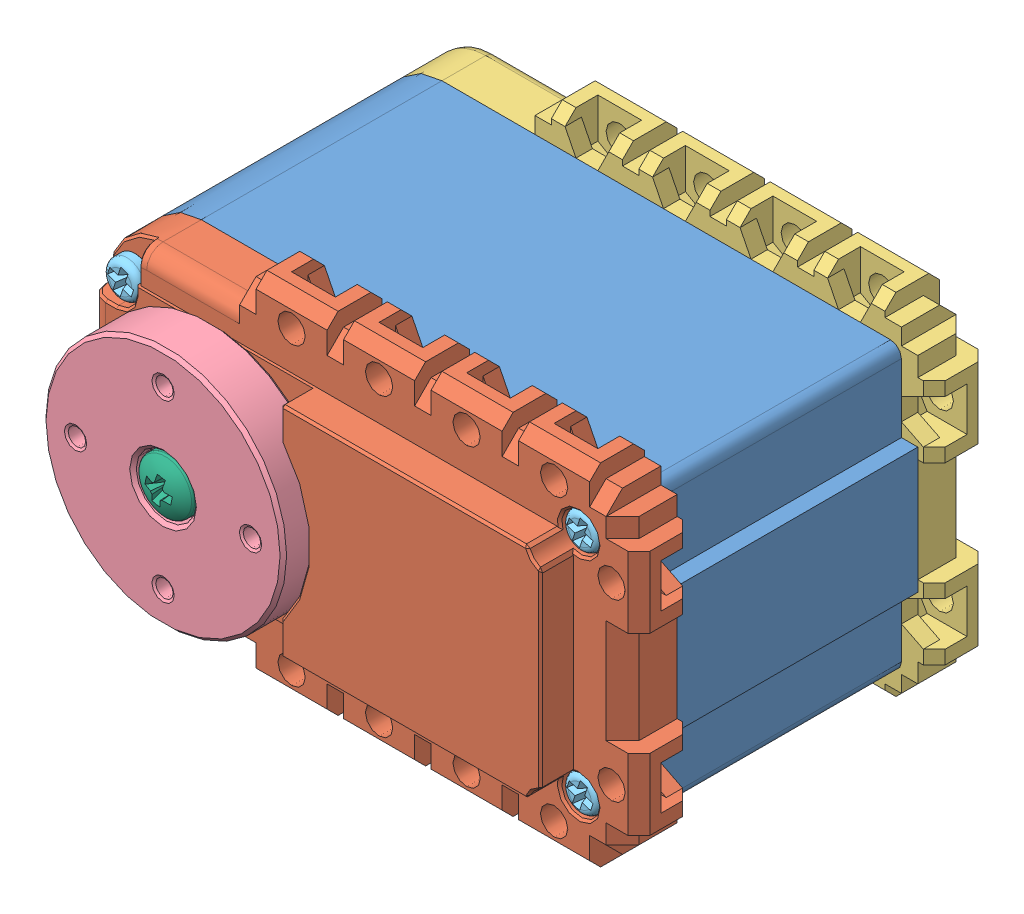
SolidWorks assembly AX-12Amotor, configuration Default. Lengths in mm.
Overall size (50 32 40.55).
9 component instances, 6 part files, 36 mates.
Components (placement in the parent):
- AX-12A-01-1: AX-12A-01 [Default] at origin size (48.5 26 22)
- AX-12A-02-1: AX-12A-02 [Default] at (0 0 13.5) size (50 32 8)
- AX-12A-03-1: AX-12A-03 [Default] at (0 0 -13.5) x (1 0 0) z (0 0 -1) size (50 32 8)
- AX-12A-04-1: AX-12A-04 [Default] at (0 0 21) size (22 22 6.7)
- SetScrew-5: SetScrew [Default] at (33 10.4 14.5) x (0.31498 0.949098 0) z (0 0 -1) size (3.3 3.3 29.44)
- SetScrew-6: SetScrew [Default] at (-9 9.25 14.5) x (0.31498 0.949098 0) z (0 0 -1) size (3.3 3.3 29.44)
- SetScrew-7: SetScrew [Default] at (-9 -9.25 14.5) x (-0.839745 -0.542981 0) z (0 0 -1) size (3.3 3.3 29.44)
- SetScrew-8: SetScrew [Default] at (33 -10.4 14.5) x (0.31498 0.949098 0) z (0 0 -1) size (3.3 3.3 29.44)
- pan head cross recess screw_iso-1: pan head cross recess screw_iso [ISO 7045 - M2.5 x 8 - Z --- 8C] at (0 0 21.6) x (0 0 -1) z (0.97903 -0.203716 0) size (10.05 5 5)
Mates (geometry in assembly coordinates):
- Coincident1: coincident: plane of AX-12A-01-1 through (0 0 11) normal (0 0 1); plane of AX-12A-02-1 through (0 0 11) normal (0 0 -1)
- Coincident2: coincident: plane of AX-12A-01-1 through (0 0 0) normal (1 0 0); plane of AX-12A-02-1 through (0 0 13.5) normal (1 0 0)
- Coincident3: coincident: plane of AX-12A-01-1 through (0 0 0) normal (0 1 0); plane of AX-12A-02-1 through (0 0 13.5) normal (0 1 0)
- Coincident4: coincident: plane of AX-12A-01-1 through (0 0 -11) normal (0 0 -1); plane of AX-12A-03-1 through (0 0 -11) normal (0 0 1)
- Coincident5: coincident: plane of AX-12A-01-1 through (0 0 0) normal (1 0 0); plane of AX-12A-03-1 through (0 0 -13.5) normal (1 0 0)
- Coincident6: coincident: plane of AX-12A-01-1 through (0 0 0) normal (0 1 0); plane of AX-12A-03-1 through (0 0 -13.5) normal (0 -1 0)
- Concentric1: concentric: cylinder of AX-12A-02-1 through (0 0 13.75) axis (0 0 1) radius 4.75; cylinder of AX-12A-04-1 through (0 0 21) axis (0 0 -1) radius 4.5
- Distance1: distance = 5 mm: plane of AX-12A-02-1 through (0 0 16) normal (0 0 1); plane of AX-12A-04-1 through (0 2.75 21) normal (0 0 1)
- Coincident7: coincident: plane of AX-12A-04-1 through (0 0 21) normal (1 0 0); plane of assembly through (0 0 0) normal (1 0 0)
- Concentric2: concentric: cylinder of AX-12A-02-1 through (33 10.4 11) axis (0 0 1) radius 1; cylinder of SetScrew-5 through (33 10.4 14.5) axis (0 0 1) radius 0.85
- Coincident8: coincident: plane of AX-12A-02-1 through (0 0 14.5) normal (0 0 1); plane of SetScrew-5 through (33.8067 10.1323 14.5) normal (0 0 -1)
- Concentric3: concentric: cylinder of AX-12A-02-1 through (-9 9.25 11) axis (0 0 1) radius 1; cylinder of SetScrew-6 through (-9 9.25 14.5) axis (0 0 1) radius 0.85
- Coincident9: coincident: plane of AX-12A-02-1 through (0 0 14.5) normal (0 0 1); plane of SetScrew-6 through (-8.1933 8.9823 14.5) normal (0 0 -1)
- Concentric4: concentric: cylinder of AX-12A-02-1 through (-9 -9.25 11) axis (0 0 1) radius 1; cylinder of SetScrew-7 through (-9 -9.25 14.5) axis (0 0 1) radius 0.85
- Coincident10: coincident: plane of AX-12A-02-1 through (0 0 14.5) normal (0 0 1); plane of SetScrew-7 through (-9.4615 -8.5362 14.5) normal (0 0 -1)
- Concentric5: concentric: cylinder of AX-12A-02-1 through (33 -10.4 11) axis (0 0 1) radius 1; cylinder of SetScrew-8 through (33 -10.4 14.5) axis (0 0 1) radius 0.85
- Coincident11: coincident: plane of AX-12A-02-1 through (0 0 14.5) normal (0 0 1); plane of SetScrew-8 through (33.8067 -10.6677 14.5) normal (0 0 -1)
- Concentric71: concentric: cylinder of AX-12A-04-1 through (0 0 21) axis (0 0 -1) radius 2.75; cylinder of pan head cross recess screw_iso-1 through (0 0 47) axis (0 0 1) radius 2.5
- Coincident131: coincident: plane of AX-12A-04-1 through (0 2.75 19.5) normal (0 0 1); plane of pan head cross recess screw_iso-1 through (0.2546 1.2238 19.5) normal (0 0 -1)
- Coincident136: coincident: plane of AX-12A-02-1 through (0 0 16) normal (0 0 1); plane of ? through (35.75 -18 16) normal (0 0 -1)
- Coincident139: coincident: cylinder of AX-12A-02-1 through (30.75 -13.5 10.999) axis (0 0 1) radius 1.25; circle of ?
- Concentric79: concentric: circle of AX-12A-02-1; circle of ?
- Coincident156: coincident: plane of ? through (114.2121 10.8 139.7397) normal (0 1 0); plane of ? through (114.2121 10.8 139.7397) normal (0 -1 0)
- Concentric90: concentric: circle of ?; circle of ?
- Coincident158: coincident: plane of ? through (114.2121 -11.2 139.7397) normal (0 -1 0); plane of ? through (114.2121 -11.2 139.7397) normal (0 1 0)
- Coincident159: coincident: circle of ?; circle of ?
- Concentric91: concentric: circle of ?; circle of ?
- Coincident162: coincident: circle of ?; circle of ?
- Concentric95: concentric: circle of ?; circle of ?
- Coincident166: coincident: plane of ? through (114.2121 -16.45 139.7397) normal (0 -1 0); plane of ? through (118.5984 -16.45 140.7451) normal (0 1 0)
- Coincident178: coincident: plane of AX-12A-04-1 through (0 2.75 21) normal (0 0 1); plane of ? through (-12.5 20.25 21) normal (0 0 -1)
- Concentric112: concentric: circle of AX-12A-04-1; circle of ?
- Concentric114: concentric: circle of AX-12A-04-1; circle of ?
- Coincident206: coincident: plane of ? through (116.8926 -23.15 140.3541) normal (0 -1 0); plane of ? through (148.8368 -23.15 111.7686) normal (0 1 0)
- Concentric116: concentric: circle of ?; circle of ?
- Concentric119: concentric: circle of ?; circle of ?
